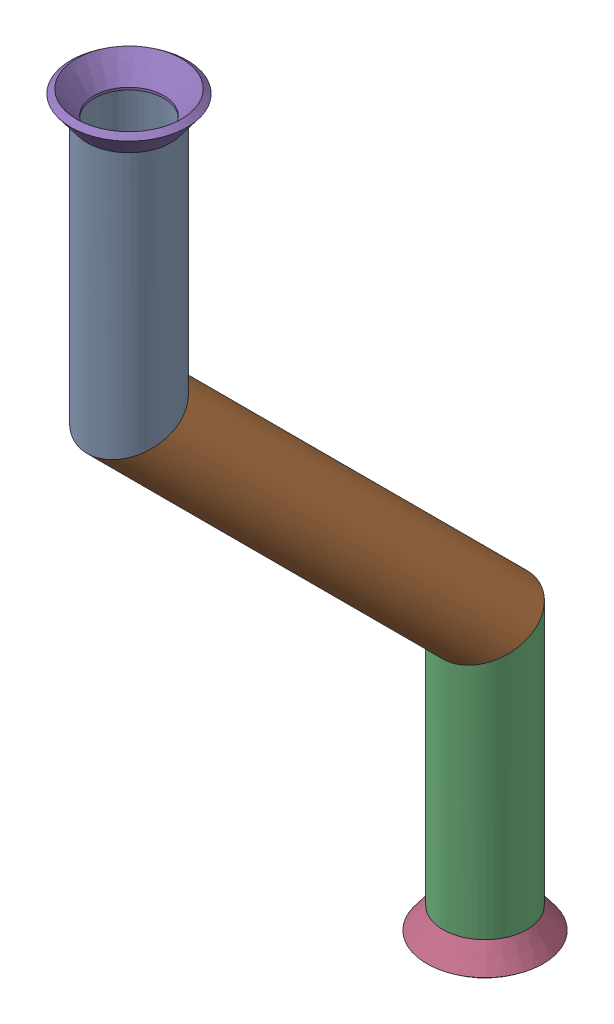
SolidWorks assembly Pipe 20, configuration Default. Lengths in mm.
Overall size (17.59 137.86 71.48).
3 component instances, 2 part files, 4 mates.
Components (placement in the parent):
- Part8-1: Part8 [Default<As Machined>] at origin size (12.7 130.08 66.58)
- Flared pipe end - .5 inch-1: Flared pipe end - .5 inch [Default<As Machined>] at (0 -184.999 248.6906) x (1 0 -0.00017) z (0 -1 0) size (17.59 17.59 3.89)
- Flared pipe end - .5 inch-2: Flared pipe end - .5 inch [Default<As Machined>] at (0 -54.9174 302.5722) x (1 0 0.00017) z (0 1 0) size (17.59 17.59 3.89)
Mates (geometry in assembly coordinates):
- Coincident1029: coincident: plane of Part8-1 through (0 -184.999 248.6906) normal (0 -1 0); plane of Flared pipe end - .5 inch-1 through (0.0009 -184.999 253.9738) normal (0 1 0)
- Concentric657: concentric: circle of Part8-1; circle of Flared pipe end - .5 inch-1
- Coincident1027: coincident: plane of Part8-1 through (0 -54.9174 302.5722) normal (0 1 0); plane of Flared pipe end - .5 inch-2 through (0.0009 -54.9174 297.289) normal (0 -1 0)
- Concentric656: concentric: circle of Part8-1; circle of Flared pipe end - .5 inch-2
